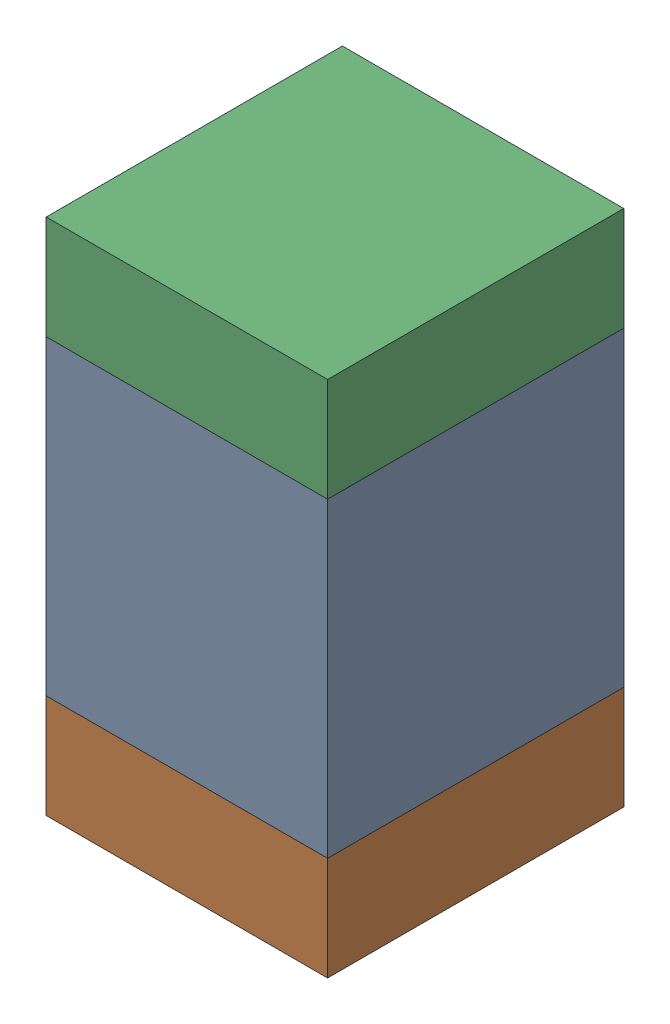
SolidWorks assembly C317_2PCB, configuration Default. Lengths in mm.
Overall size (0.95 1.75 1).
6 component instances, 2 part files, 0 mates.
Components (placement in the parent):
- 761616384-1: 761616384 [Default] at (128.1 84.2 -2.6638) size (0.95 1.05 1)
  - Extruded_5-1: Extruded_5 [Default] at origin size (0.95 1.05 1)
- 761616520-1: 761616520 [Default] at (128.1 83.5 -2.6638) size (0.95 0.35 1)
  - Extruded_6-1: Extruded_6 [Default] at origin size (0.95 0.35 1)
- 761616520-2: 761616520 [Default] at (128.1 84.9 -2.6638) size (0.95 0.35 1)
  - Extruded_6-1: Extruded_6 [Default] at origin size (0.95 0.35 1)
